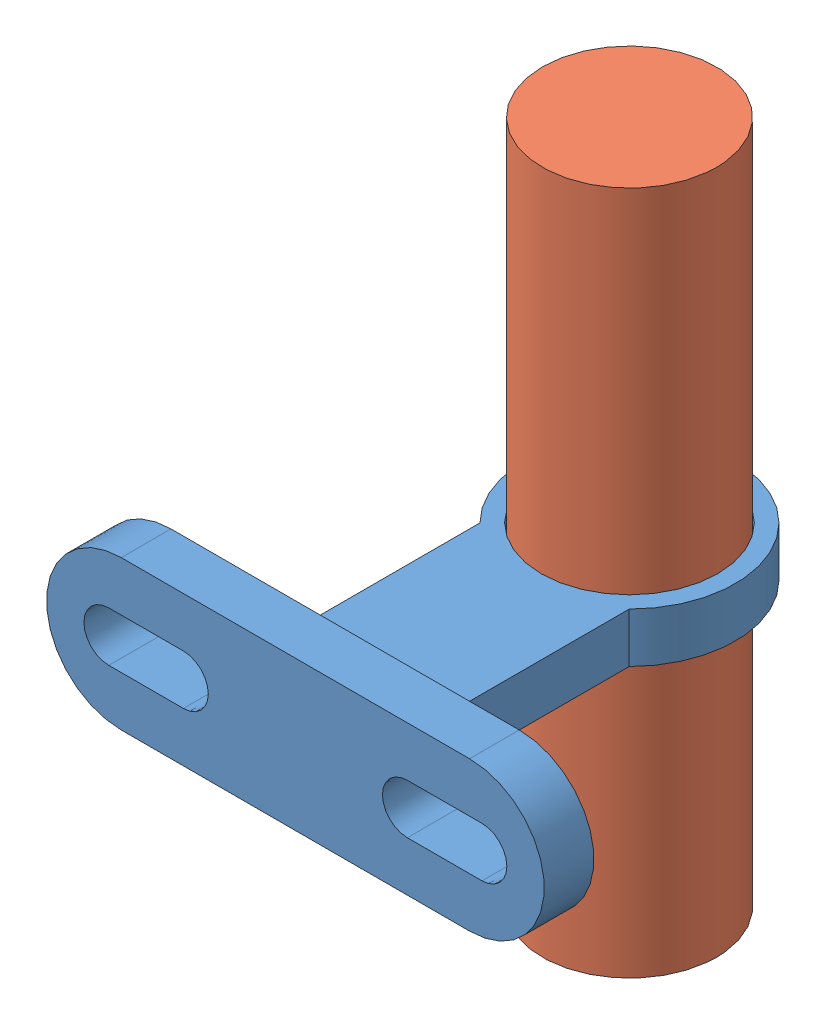
SolidWorks assembly [SPCN] Assem Nháp, configuration Default. Lengths in mm.
Overall size (200 275 176.78).
2 component instances, 2 part files, 1 mates.
Components (placement in the parent):
- [SPCN] Ring-Situated Pad-1: [SPCN] Ring-Situated Pad [Default] at (-98.1429 230.2478 456.5527) size (200 60 176.78)
- [SPCN] Actuator Rod-2: [SPCN] Actuator Rod [Default] at (-98.1429 391.4537 456.5527) x (1 0 0) z (0 -1 0) size (70 70 275)
Mates (geometry in assembly coordinates):
- Concentric1: concentric anti-aligned: cylinder of [SPCN] Ring-Situated Pad-1 through (-98.1429 250.2478 456.5527) axis (0 -1 0) radius 35.5; cylinder of [SPCN] Actuator Rod-2 through (-98.1429 116.4537 456.5527) axis (0 1 0) radius 35
